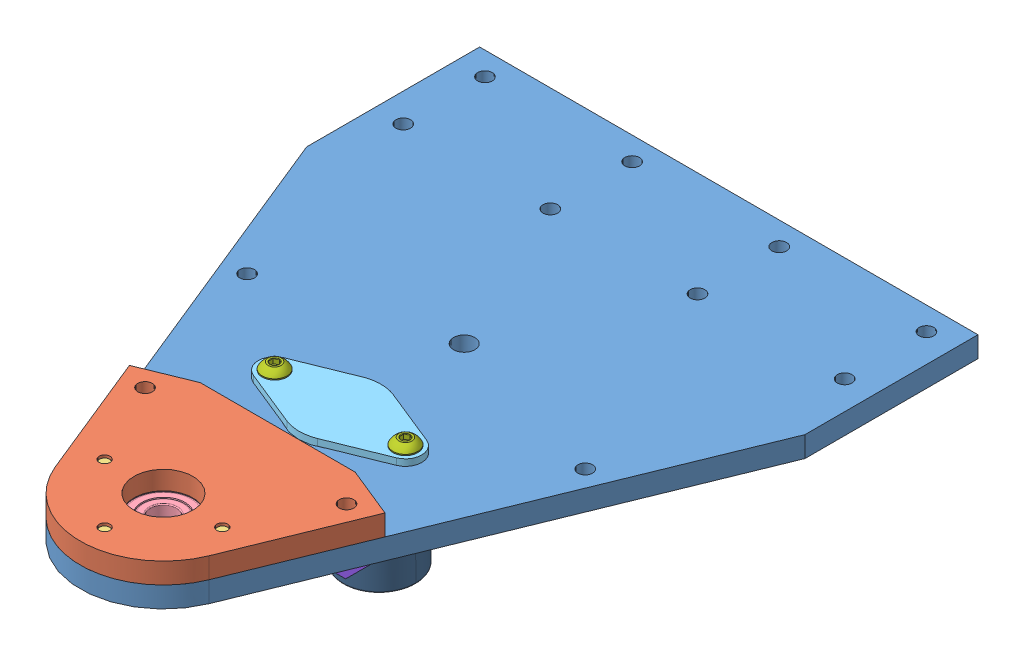
SolidWorks assembly Aft Plate Assembly, configuration Default. Lengths in mm.
Overall size (152.4 54.07 210.99).
18 component instances, 11 part files, 2 mates.
Components (placement in the parent):
- Main Plate Sub Asmbly_1-1: Main Plate Sub Asmbly_1 [Default] at origin size (152.4 12.84 210.99)
  - Main Plate-1: Main Plate [Default] at origin size (152.4 6.35 210.99)
  - Bearing Plate-1: Bearing Plate [Default] at origin size (78.15 6.35 60.33)
  - 91294A192 - M4 x 0.7 mm, 12 mm Long Hex Drive Flat Head Screw-1: 91294A192 - M4 x 0.7 mm, 12 mm Long Hex Drive Flat Head Screw [Default] at (0 -33.3375 171.3144) x (1 0 0) z (0 -1 0) size (8 8 12.14)
  - 91294A192 - M4 x 0.7 mm, 12 mm Long Hex Drive Flat Head Screw-2: 91294A192 - M4 x 0.7 mm, 12 mm Long Hex Drive Flat Head Screw [Default] at (-18 -33.3375 153.3144) x (1 0 0) z (0 -1 0) size (8 8 12.14)
  - 91294A192 - M4 x 0.7 mm, 12 mm Long Hex Drive Flat Head Screw-3: 91294A192 - M4 x 0.7 mm, 12 mm Long Hex Drive Flat Head Screw [Default] at (18 -33.3375 153.3144) x (1 0 0) z (0 -1 0) size (8 8 12.14)
  - 8x22x7+Bearing+-+6082Z-8x22x7_6082Z-8x22x7-1: 8x22x7+Bearing+-+6082Z-8x22x7_6082Z-8x22x7 [Default] at (0 -29.8375 153.3144) x (1 0 0) z (0 -1 0) size (22 22 7.01)
- FRT-D2-152-G1_1-1: FRT-D2-152-G1_1 [Default] at (0 -24.9875 99.3144) x (-1 0 0) z (0 -1 0) size (50 25 19)
  - FRT-D2-152-1: FRT-D2-152 [Default] at origin size (50 25 19)
  - FRT-D2-G1 12mm Gear-2: FRT-D2-G1 12mm Gear [Default] at (0 0 14) x (0 -1 0) z (0 0 1) size (14 14 5)
- 91239A150-1: 91239A150 [Default] at (20 -22.7875 99.3144) x (-1 0 0) z (0 1 0) size (7.65 7.69 18.7)
- 91239A150-2: 91239A150 [Default] at (-20 -22.7875 99.3144) x (-1 0 0) z (0 1 0) size (7.65 7.69 18.7)
- Roll Sensor Asmbly-1: Roll Sensor Asmbly [Default] x (-1 0 0) z (0 0 1) size (50.16 41.37 31.85)
  - Roll Sensor Mount Main-1: Roll Sensor Mount Main [Default] at origin size (50.16 27.53 31.75)
  - 94180A351-1: 94180A351 [Default] at (-20 33.3375 99.3144) x (1 0 0) z (0 -1 0) size (6.35 6.35 4.7)
  - 94180A351-2: 94180A351 [Default] at (20 33.3375 99.3144) x (1 0 0) z (0 -1 0) size (6.35 6.35 4.7)
  - 6127V1AxxxL.5FS-1: 6127V1AxxxL.5FS [6127V1A360L.5FS] at (0 61.2423 87.3281) x (1 0 0) z (0 0.011977 0.999928) size (22.23 35.66 22.23)
  - Roll Damper Gear-1: Roll Damper Gear [Default] at (0 38.9173 87.5956) x (-1 0 0) z (0 0.999928 -0.011977) size (14 14 10)
Mates (geometry in assembly coordinates):
- Coincident7: coincident: plane of FRT-D2-152-G1_1-1 through (0 -24.9875 99.3144) normal (-1 0 0); plane of Roll Sensor Asmbly-1/6127V1AxxxL.5FS-1 through (0 -61.2423 87.3281) normal (-1 0 0)
- Tangent2: tangent: circle of FRT-D2-152-G1_1-1/FRT-D2-G1 12mm Gear-2; circle of Roll Sensor Asmbly-1/Roll Damper Gear-1
